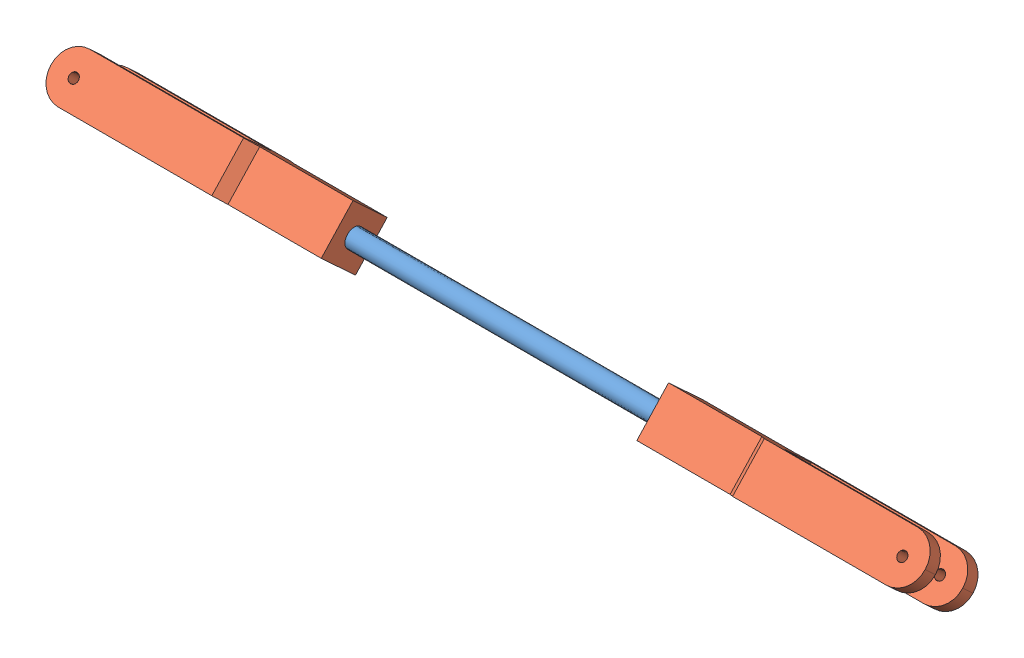
SolidWorks assembly Servo Rod, configuration Default. Lengths in mm.
Overall size (93.73 8.43 8.53).
3 component instances, 2 part files, 3 mates.
Components (placement in the parent):
- Rod-1: Rod [Default] at origin size (40 2 2)
- Servo Connector-1: Servo Connector [Default] at (35.4839 0 0) x (0 -0.679858 -0.733344) z (0 -0.733344 0.679858) size (7 29.95 5)
- Servo Connector-2: Servo Connector [Default] at (1.651 0 0) x (0 -0.679858 -0.733344) z (0 0.733344 -0.679858) size (7 29.95 5)
Mates (geometry in assembly coordinates):
- Concentric1: concentric aligned: cylinder of Rod-1 through (40 0 0) axis (-1 0 0) radius 1; cylinder of Servo Connector-1 through (45.4839 0 0) axis (-1 0 0) radius 1
- Concentric2: concentric anti-aligned: cylinder of Rod-1 through (40 0 0) axis (-1 0 0) radius 1; cylinder of Servo Connector-2 through (-8.349 0 0) axis (1 0 0) radius 1
- Parallel1: parallel anti-aligned: line of Servo Connector-1 through (35.4839 -0.1337 3.533) axis (0 -0.679858 -0.733344); line of Servo Connector-2 through (1.651 -3.533 -0.1337) axis (0 0.679858 0.733344)
